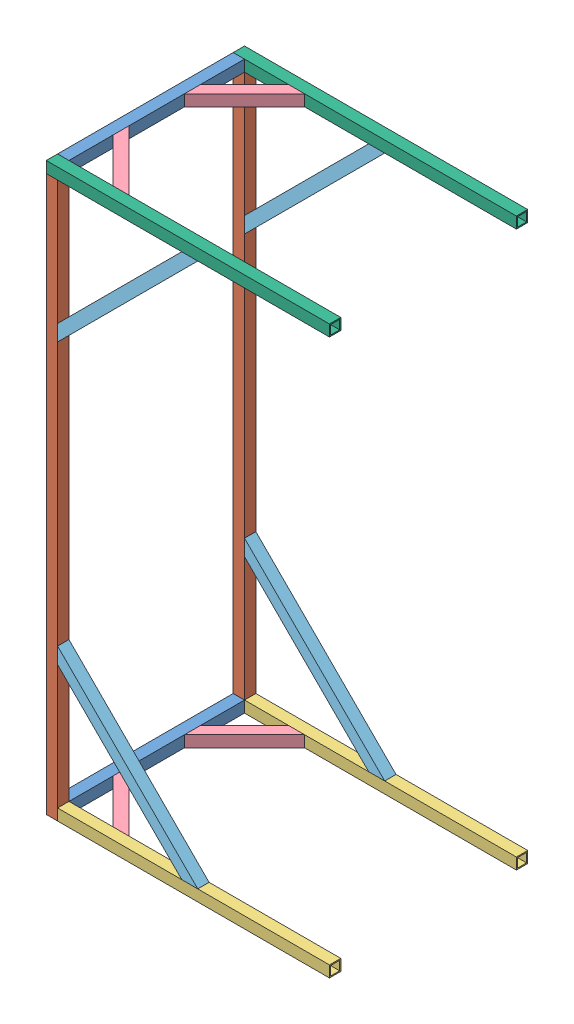
SolidWorks assembly 010112_frame_half, configuration Default. Lengths in mm.
Overall size (1000 2000 700).
17 component instances, 6 part files, 16 mates.
Components (placement in the parent):
- 010101_ST_40x4x620-1: 010101_ST_40x4x620 [Default] at origin size (40 40 620)
- 010102_ST_40x4x1960-1: 010102_ST_40x4x1960 [Default] at (0 -20 640) x (0 0 -1) z (0 1 0) size (40 40 1960)
- 010115_ST_40x4x960-1: 010115_ST_40x4x960 [Default] at (520 0 640) x (0 0 1) z (-1 0 0) size (40 40 960)
- 010109_ST_40x4x300_chamfered-1: 010109_ST_40x4x300_chamfered [Default] at (5.8579 0 422.0101) x (0.707107 0 -0.707107) z (0.707107 0 0.707107) size (40 40 300)
- 010106_ST_40x4x700_chamfered-1: 010106_ST_40x4x700_chamfered [Default] at (500.8326 5.8579 640) x (0.707107 0.707107 0) z (-0.707107 0.707107 0) size (40 40 700)
- 010105_ST_40x4x1000-3: 010105_ST_40x4x1000 [Default] at (480 1960 640) x (0 0 1) z (-1 0 0) size (40 40 1000)
- 010101_ST_40x4x620-2: 010101_ST_40x4x620 [Default] at (0 1960 620) x (1 0 0) z (0 0 -1) size (40 40 620)
- 010106_ST_40x4x700_chamfered-2: 010106_ST_40x4x700_chamfered [Default] at (5.8579 1459.1674 640) x (0.707107 -0.707107 0) z (0.707107 0.707107 0) size (40 40 700)
- 010109_ST_40x4x300_chamfered-2: 010109_ST_40x4x300_chamfered [Default] at (217.9899 1960 634.1421) x (0.707107 0 -0.707107) z (-0.707107 0 -0.707107) size (40 40 300)
- 010101_ST_40x4x620-3: 010101_ST_40x4x620 [Default] at (0 1960 620) x (1 0 0) z (0 0 -1) size (40 40 620)
- 010109_ST_40x4x300_chamfered-3: 010109_ST_40x4x300_chamfered [Default] at (5.8579 1960 197.9899) x (0.707107 0 0.707107) z (0.707107 0 -0.707107) size (40 40 300)
- 010106_ST_40x4x700_chamfered-3: 010106_ST_40x4x700_chamfered [Default] at (500.8326 1954.1421 -20) x (0.707107 -0.707107 0) z (-0.707107 -0.707107 0) size (40 40 700)
- 010106_ST_40x4x700_chamfered-4: 010106_ST_40x4x700_chamfered [Default] at (5.8579 500.8326 -20) x (0.707107 0.707107 0) z (0.707107 -0.707107 0) size (40 40 700)
- 010105_ST_40x4x1000-4: 010105_ST_40x4x1000 [Default] at (480 1960 -20) x (0 0 -1) z (1 0 0) size (40 40 1000)
- 010115_ST_40x4x960-2: 010115_ST_40x4x960 [Default] at (480 0 -20) x (0 0 -1) z (1 0 0) size (40 40 960)
- 010109_ST_40x4x300_chamfered-4: 010109_ST_40x4x300_chamfered [Default] at (217.9899 0 -14.1421) x (0.707107 0 0.707107) z (-0.707107 0 0.707107) size (40 40 300)
- 010102_ST_40x4x1960-2: 010102_ST_40x4x1960 [Default] at (0 1940 -20) x (0 0 1) z (0 -1 0) size (40 40 1960)
Mates (geometry in assembly coordinates):
- Coincident1: coordinate: point of 010101_ST_40x4x620-1
- Coincident2: coincident anti-aligned: plane of 010101_ST_40x4x620-1 through (0 0 620) normal (0 0 1); plane of 010102_ST_40x4x1960-1 through (-20 -20 620) normal (0 0 -1)
- Coincident3: coincident aligned: plane of 010101_ST_40x4x620-1 through (-20 20 0) normal (-1 0 0); plane of 010102_ST_40x4x1960-1 through (-20 -20 660) normal (-1 0 0)
- Coincident4: coincident aligned: plane of 010101_ST_40x4x620-1 through (-20 -20 0) normal (0 -1 0); plane of 010102_ST_40x4x1960-1 through (0 -20 640) normal (0 -1 0)
- Coincident5: coincident anti-aligned: plane of 010102_ST_40x4x1960-1 through (20 -20 660) normal (1 0 0); plane of 010115_ST_40x4x960-1 through (20 0 640) normal (-1 0 0)
- Coincident6: coincident aligned: plane of 010102_ST_40x4x1960-1 through (-20 -20 660) normal (0 0 1); plane of 010115_ST_40x4x960-1 through (20 20 660) normal (0 0 1)
- Coincident7: coincident aligned: plane of 010102_ST_40x4x1960-1 through (0 -20 640) normal (0 -1 0); plane of 010115_ST_40x4x960-1 through (20 -20 620) normal (0 -1 0)
- Coincident9: coincident aligned: plane of 010101_ST_40x4x620-1 through (-20 20 0) normal (0 1 0); plane of 010109_ST_40x4x300_chamfered-1 through (-8.2843 20 436.1522) normal (0 1 0)
- Coincident10: coincident anti-aligned: plane of 010101_ST_40x4x620-1 through (20 20 0) normal (1 0 0); plane of 010109_ST_40x4x300_chamfered-1 through (20 -20 407.868) normal (-1 0 0)
- Coincident11: coincident anti-aligned: plane of 010115_ST_40x4x960-1 through (20 20 620) normal (0 0 -1); plane of 010109_ST_40x4x300_chamfered-1 through (232.132 -20 620) normal (0 0 1)
- Coincident12: coincident anti-aligned: plane of 010102_ST_40x4x1960-1 through (20 -20 660) normal (1 0 0); plane of 010106_ST_40x4x700_chamfered-1 through (20 514.9747 660) normal (-1 0 0)
- Coincident13: coincident aligned: plane of 010102_ST_40x4x1960-1 through (-20 -20 620) normal (0 0 -1); plane of 010106_ST_40x4x700_chamfered-1 through (486.6905 -8.2843 620) normal (0 0 -1)
- Coincident14: coincident anti-aligned: plane of 010115_ST_40x4x960-1 through (20 20 620) normal (0 1 0); plane of 010106_ST_40x4x700_chamfered-1 through (514.9747 20 660) normal (0 -1 0)
- Coincident15: coincident aligned: plane of 010102_ST_40x4x1960-1 through (-20 -20 660) normal (0 0 1); plane of 010105_ST_40x4x1000-3 through (-20 1980 660) normal (0 0 1)
- Coincident16: coincident aligned: plane of 010102_ST_40x4x1960-1 through (-20 -20 660) normal (-1 0 0); plane of 010105_ST_40x4x1000-3 through (-20 1960 640) normal (-1 0 0)
- Coincident17: coincident anti-aligned: plane of 010102_ST_40x4x1960-1 through (0 1940 640) normal (0 1 0); plane of 010105_ST_40x4x1000-3 through (-20 1940 620) normal (0 -1 0)
